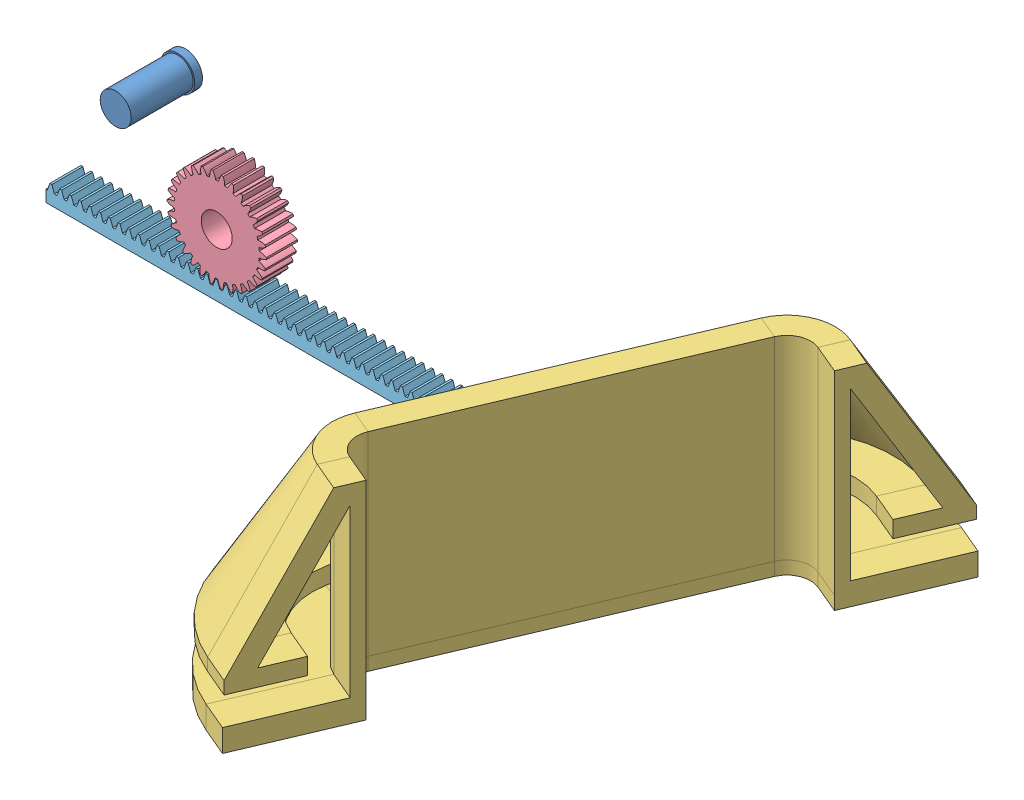
SolidWorks assembly rack & pinion 2, configuration Default. Lengths in mm.
Overall size (505.17 161.25 383.76).
6 component instances, 5 part files, 13 mates.
Components (placement in the parent):
- shaft_of_servo-2: shaft_of_servo [Default] at (0 0 -20) x (0.99967 -0.025671 0) z (0 0 1) size (22 22 45)
- rack_pusher_plate-1: rack_pusher_plate [Default] at (238.5172 -47.5804 -16.8456) x (-0.390209 0 0.920726) z (-0.920726 0 -0.390209) size (23.97 11.55 8)
- pushbuttonfinal-1: pushbuttonfinal [Default] at (353.1329 -141.5237 -85.3266) x (0 -1 0) z (-0.390209 0 0.920726) size (134 105.95 371.9)
- GEARS-1: GEARS [Default] at (-5.0411 -105.1749 -50.2553) size (250 82.11 20)
  - spur gear_am-1: spur gear_am [Metric - Spur gear 2M 30T 20PA 20FW ---S30N75H50L20N] at (0 0 -20) x (0 0 1) z (-0.095843 0.995396 0) size (20 138.88 64)
  - rack spur rectangular_am-1: rack spur rectangular_am [Metric - Rack-spur - rectangular 2M 20PA 20FW 10PH 250L---SAll] at (-110.182 -40 0) size (250 12 20)
Mates (geometry in assembly coordinates):
- Coincident1: coincident aligned: plane of ? through (0 0 0) normal (0 0 1); plane of assembly through (0 0 0) normal (0 0 1)
- Coincident2: coincident aligned: line of ? through (250 -18.7901 -40) axis (0 1 0)
- Concentric1: concentric anti-aligned: cylinder of ? through (0 0 30.0001) axis (0 0 -1) radius 10
- Coincident3: coincident aligned: plane of ? through (0 0 -20) normal (0 0 -1); plane of ? through (-18.7901 -28 -20) normal (0 0 -1)
- RackPinionMate1: rack pinion = 60 mm: line of ? through (250 -18.7901 -40) axis (0 1 0); circle of ?
- Concentric3: concentric aligned: cylinder of ? through (0 0 30.0001) axis (0 0 -1) radius 10; cylinder of shaft_of_servo-2 through (0 0 20) axis (0 0 -1) radius 10
- Coincident4: coincident anti-aligned: plane of ? through (0 0 -20) normal (0 0 -1); plane of shaft_of_servo-2 through (0 0 -20) normal (0 0 1)
- Parallel1: parallel anti-aligned: plane of ? through (231.2099 -40 -20) normal (1 0 0); plane of rack_pusher_plate-1 through (245.177 1.3314 -9.2389) normal (-1 0 0)
- Coincident7: coincident anti-aligned: plane of ? through (231.2099 -40 -20) normal (1 0 0); plane of rack_pusher_plate-1
- Coincident9: coincident anti-aligned: line of rack_pusher_plate-1 through (231.2099 -78.9846 -20.1055) axis (0 -1 0); line of assembly
- Coincident11: coincident anti-aligned: plane of ? through (231.2099 -40 -20) normal (1 0 0); plane of rack_pusher_plate-1
- Parallel2: parallel anti-aligned: plane of rack_pusher_plate-1 through (215.3641 -72.7721 0.5124) normal (0.460363 0.866025 0.195105); plane of pushbuttonfinal-1 through (286.4 -60.2067 -113.6083) normal (-0.460363 -0.866025 -0.195105)
- Coincident13: coincident anti-aligned: plane of rack_pusher_plate-1 through (243.3176 -55.9776 9.1009) normal (0.797372 -0.5 0.337931); plane of pushbuttonfinal-1 through (231.2321 -15.9746 96.8058) normal (-0.797372 0.5 -0.337931)
